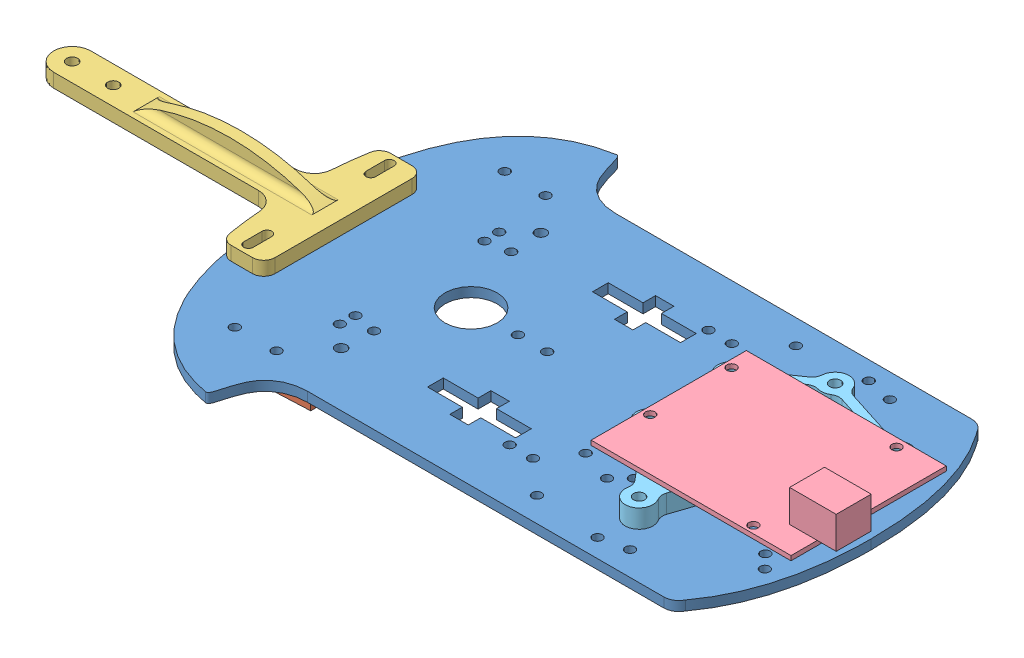
SolidWorks assembly Assem1, configuration Default. Lengths in mm.
Overall size (286.08 66.54 141.27).
5 component instances, 5 part files, 14 mates.
Components (placement in the parent):
- lab3plate_2017-1: lab3plate_2017 [Default] at origin size (197.89 3.3 141.27)
- IR_short_mount-1: IR_short_mount [Default] x (-1 0 0) z (0 -1 0) size (16.85 54.67 44.33)
- Far_mount-1: Far_mount [Default] at (0 3.3 0) x (1 0 0) z (0 1 0) size (99.4 54.67 11.2)
- arduino_mock-1: arduino_mock [Default] at (54.2892 11.21 -19.01) x (1 0 0) z (0 0 -1) size (75.08 12.56 53.26)
- Arduino_mount-1: Arduino_mount [Default] at (0 3.3 0) x (1 0 0) z (0 1 0) size (61.42 76.78 6.35)
Mates (geometry in assembly coordinates):
- InPlace1: in place: plane of lab3plate_2017-1 through (117.7678 0 28.2624) normal (0 -1 0); plane of IR_short_mount-1 through (0 0 0) normal (0 -1 0); moOrthogonalPlaneRef_w of lab3plate_2017-1 through (117.7678 0 28.2624) normal (0 -1 0); plane of IR_short_mount-1 through (0 0 0) normal (0 0 -1); plane of lab3plate_2017-1 through (117.7678 0 28.2624) normal (0 -1 0); plane of IR_short_mount-1 through (0 0 0) normal (-1 0 0); plane of lab3plate_2017-1 through (117.7678 0 28.2624) normal (0 -1 0); unknown of IR_short_mount-1
- Coincident1: coincident: plane of lab3plate_2017-1; plane of IR_short_mount-1
- Coincident2: coincident: moOrthogonalPlaneRef_w of lab3plate_2017-1 through (0 0 0) normal (0 0 -1); plane of IR_short_mount-1 through (0 0 0) normal (0 0 -1)
- Coincident3: coincident: moOrthogonalPlaneRef_w of lab3plate_2017-1 through (0 0 0) normal (1 0 0); plane of IR_short_mount-1 through (0 0 0) normal (-1 0 0)
- InPlace2: in place: plane of lab3plate_2017-1 through (117.7678 3.3 28.2624) normal (0 1 0); plane of ? through (0 3.3 0) normal (0 1 0); plane of lab3plate_2017-1 through (117.7678 3.3 28.2624) normal (0 1 0); plane of ? through (0 3.3 0) normal (0 0 -1); plane of lab3plate_2017-1 through (117.7678 3.3 28.2624) normal (0 1 0); plane of ? through (0 3.3 0) normal (1 0 0); plane of lab3plate_2017-1 through (117.7678 3.3 28.2624) normal (0 1 0); unknown of ?
- Coincident4: coincident: plane of lab3plate_2017-1; plane of Far_mount-1
- Coincident5: coincident: moOrthogonalPlaneRef_w of lab3plate_2017-1 through (0 3.3 0) normal (0 0 -1); plane of Far_mount-1 through (0 3.3 0) normal (0 0 -1)
- Coincident6: coincident: moOrthogonalPlaneRef_w of lab3plate_2017-1 through (0 3.3 0) normal (-1 0 0); plane of Far_mount-1 through (0 3.3 0) normal (1 0 0)
- Distance1: distance = 6.35 mm: plane of arduino_mock-1 through (54.2892 9.65 -19.01) normal (0 -1 0); plane of lab3plate_2017-1 through (117.7678 3.3 28.2624) normal (0 1 0)
- Width1: width: plane of lab3plate_2017-1 through (-19.4127 3.3 52.8292) normal (0 0 1); plane of lab3plate_2017-1 through (-19.4127 3.3 -52.8292) normal (0 0 -1); plane of arduino_mock-1 through (120.3292 9.65 -26.63) normal (0 0 -1); plane of arduino_mock-1 through (120.3292 9.65 26.63) normal (0 0 1)
- InPlace4: in place: plane of lab3plate_2017-1 through (117.7678 3.3 28.2624) normal (0 1 0); plane of ? through (0 3.3 0) normal (0 1 0); plane of lab3plate_2017-1 through (117.7678 3.3 28.2624) normal (0 1 0); plane of ? through (0 3.3 0) normal (0 0 -1); plane of lab3plate_2017-1 through (117.7678 3.3 28.2624) normal (0 1 0); plane of ? through (0 3.3 0) normal (1 0 0); plane of lab3plate_2017-1 through (117.7678 3.3 28.2624) normal (0 1 0); unknown of ?
- Coincident11: coincident: plane of lab3plate_2017-1; plane of Arduino_mount-1
- Coincident12: coincident: moOrthogonalPlaneRef_w of lab3plate_2017-1 through (0 3.3 0) normal (0 0 -1); plane of Arduino_mount-1 through (0 3.3 0) normal (0 0 -1)
- Coincident13: coincident: moOrthogonalPlaneRef_w of lab3plate_2017-1 through (0 3.3 0) normal (-1 0 0); plane of Arduino_mount-1 through (0 3.3 0) normal (1 0 0)
